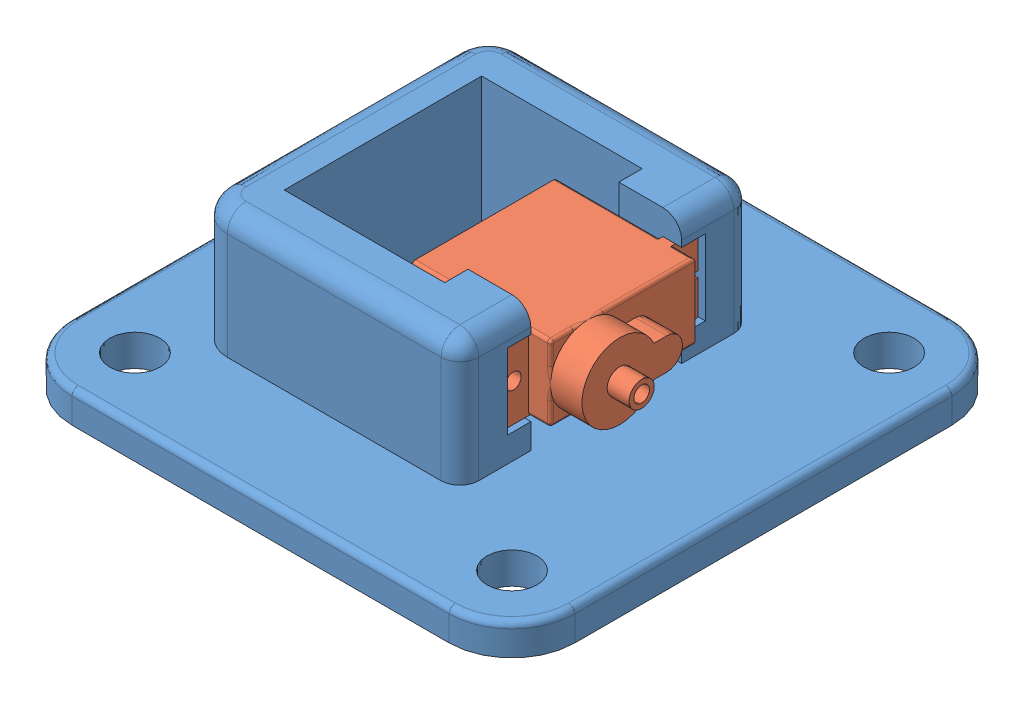
SolidWorks assembly 装配体1, configuration 默认. Lengths in mm.
Overall size (80 25 80).
2 component instances, 2 part files, 2 mates.
Components (placement in the parent):
- 底座-1: 底座 [默认] at (-10.4198 -19.0964 80) size (80 25 80)
- 舵机1-1: 舵机1 [默认] at (-14.9198 -4.0964 79.8726) x (0 0 -1) z (0 -1 0) size (31 30.5 12)
Mates (geometry in assembly coordinates):
- 重合1: coincident: plane of 底座-1 through (1.5802 -19.0964 80) normal (1 0 0); plane of 舵机1-1 through (1.5802 -4.339 93.7753) normal (-1 0 0)
- 宽度1: width anti-aligned: plane of 底座-1 through (1.5802 1.9036 80) normal (0 -1 0); plane of 舵机1-1 through (1.5802 -10.0964 80) normal (0 1 0); plane of 底座-1 through (1.5802 1.9036 68.3726) normal (0 1 0); plane of 舵机1-1 through (1.5802 -10.0964 68.3726) normal (0 -1 0)
